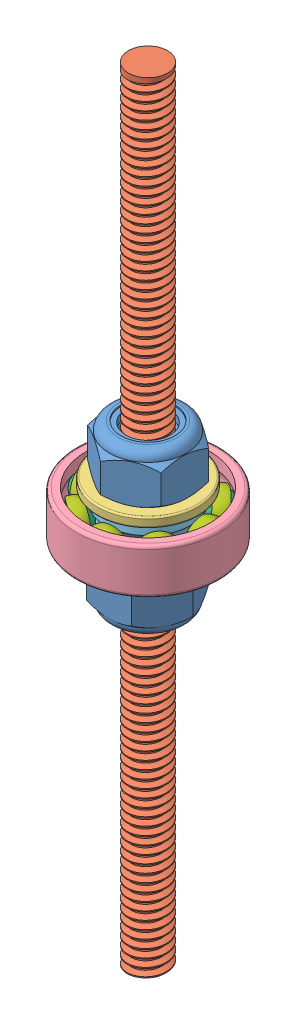
SolidWorks assembly BB_Rod_Assembly, configuration Default. Lengths in mm.
Overall size (23.24 121.11 23.24).
18 component instances, 7 part files, 11 mates.
Components (placement in the parent):
- M8_self_lock_Nut-1: M8_self_lock_Nut [Valor predeterminado] at (0 71 0) x (-0.837169 0 -0.546944) z (0 -1 0) size (15.1 12 8.06)
- M8_Threaded_Rod-1: M8_Threaded_Rod [Default] at origin size (6.18 121.11 6.93)
- M8_Washer-1: M8_Washer [Default] at (0 63.5 0) x (1 0 0) z (0 1 0) size (15.5 15.5 1.5)
- BB_Assembly-1: BB_Assembly [Default] at (0 60 0) x (0 -1 0) z (-0.058052 0 0.998314) size (7 22 22)
  - BB_OuterRing-1: BB_OuterRing [Default] at origin size (7 22 22)
  - BB_InnerRing-1: BB_InnerRing [Default] x (1 0 0) z (0 0.97954 -0.20125) size (7 13 13)
  - BB_Ball-1: BB_Ball [Default] at (0 1.61 7.8363) x (-1 0 0) z (0 -0.97954 0.20125) size (4.5 4.5 4.5)
  - BB_Cage-1: BB_Cage [Default] x (0 -0.20125 -0.97954) z (1 0 0) size (18 18 2.77)
  - BB_Ball-2: BB_Ball [Default] at (0 6.6796 4.4027) x (-1 0 0) z (0 -0.550334 0.834945) size (4.5 4.5 4.5)
  - BB_Ball-3: BB_Ball [Default] at (0 7.8363 -1.61) x (-1 0 0) z (0 0.20125 0.97954) size (4.5 4.5 4.5)
  - BB_Ball-4: BB_Ball [Default] at (0 4.4027 -6.6796) x (-1 0 0) z (0 0.834945 0.550334) size (4.5 4.5 4.5)
  - BB_Ball-5: BB_Ball [Default] at (0 -1.61 -7.8363) x (-1 0 0) z (0 0.97954 -0.20125) size (4.5 4.5 4.5)
  - BB_Ball-6: BB_Ball [Default] at (0 -6.6796 -4.4027) x (-1 0 0) z (0 0.550334 -0.834945) size (4.5 4.5 4.5)
  - BB_Ball-7: BB_Ball [Default] at (0 -7.8363 1.61) x (-1 0 0) z (0 -0.20125 -0.97954) size (4.5 4.5 4.5)
  - BB_Ball-8: BB_Ball [Default] at (0 -4.4027 6.6796) x (-1 0 0) z (0 -0.834945 -0.550334) size (4.5 4.5 4.5)
  - BB_Cage-2: BB_Cage [Default] x (0 0.20125 0.97954) z (-1 0 0) size (18 18 2.77)
- M8_Washer-3: M8_Washer [Default] at (0 55 0) x (1 0 0) z (0 1 0) size (15.5 15.5 1.5)
- M8_self_lock_Nut-15: M8_self_lock_Nut [Valor predeterminado] at (0 49 0) x (1 0 0) z (0 1 0) size (15.1 12 8.06)
Mates (geometry in assembly coordinates):
- Concentric1: concentric anti-aligned: cylinder of M8_Threaded_Rod-1 through (0 120 0) axis (0 -1 0) radius 3; cylinder of BB_Assembly-1/BB_InnerRing-1 through (0 102.3909 0) axis (0 1 0) radius 5
- Concentric3: concentric anti-aligned: cylinder of M8_Washer-1 through (0 65 0) axis (0 -1 0) radius 4.125; circle of BB_Assembly-1/BB_InnerRing-1
- Coincident2: coincident anti-aligned: plane of M8_Washer-1 through (0 63.5 0) normal (0 -1 0); plane of BB_Assembly-1/BB_InnerRing-1 through (-0.7202 63.5 -4.9479) normal (0 1 0)
- Concentric4: concentric aligned: circle of M8_self_lock_Nut-1; circle of M8_Washer-1
- Coincident3: coincident anti-aligned: plane of M8_self_lock_Nut-1 through (0 65 0) normal (0 -1 0); plane of M8_Washer-1 through (0 65 0) normal (0 1 0)
- Concentric5: concentric anti-aligned: circle of BB_Assembly-1/BB_InnerRing-1; circle of M8_Washer-3
- Coincident8: coincident anti-aligned: plane of BB_Assembly-1/BB_InnerRing-1 through (-0.7202 56.5 -4.9479) normal (0 -1 0); plane of M8_Washer-3 through (0 56.5 0) normal (0 1 0)
- Concentric6: concentric aligned: circle of M8_Washer-3; circle of M8_self_lock_Nut-15
- Coincident9: coincident anti-aligned: plane of M8_Washer-3 through (0 55 0) normal (0 -1 0); plane of M8_self_lock_Nut-15 through (0 55 0) normal (0 1 0)
- Coincident10: coordinate: point of M8_Threaded_Rod-1
- Width2: width anti-aligned: plane of BB_Assembly-1/BB_OuterRing-1 through (9.484 63.5 0.5515) normal (0 1 0); plane of M8_Threaded_Rod-1 through (9.484 56.5 0.5515) normal (0 -1 0); plane of BB_Assembly-1/BB_OuterRing-1 through (0 0 0) normal (0 -1 0); plane of M8_Threaded_Rod-1 through (0 120 0) normal (0 1 0)
